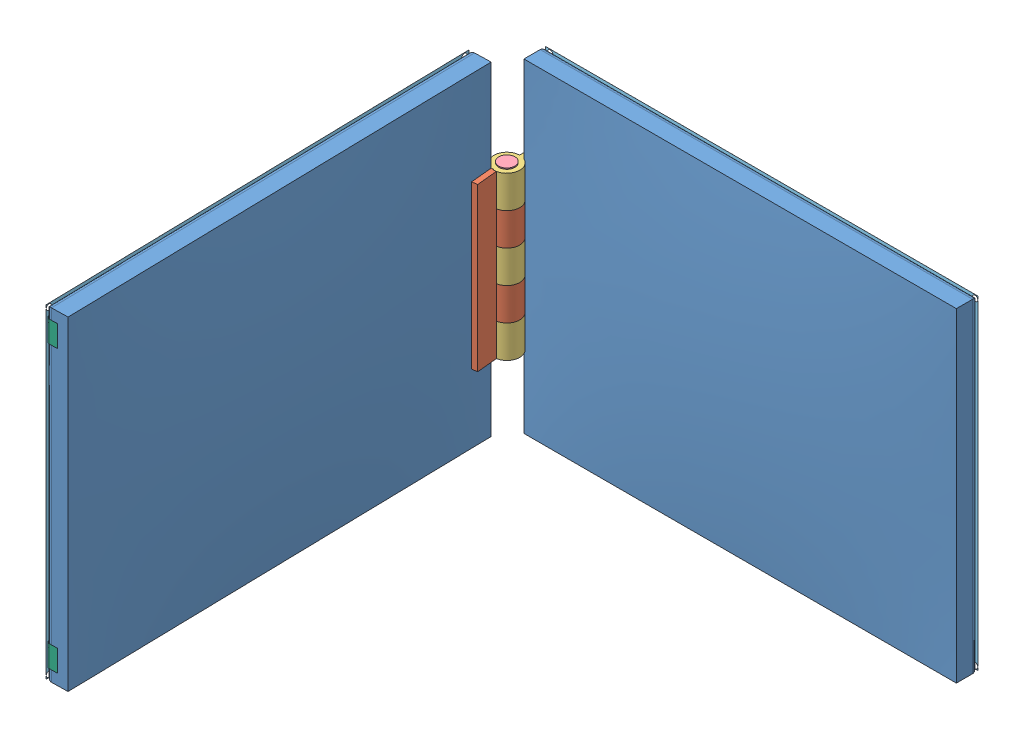
SolidWorks assembly Foldable Seat, configuration Default. Lengths in mm.
Overall size (427.7 305 443.01).
9 component instances, 6 part files, 19 mates.
Components (placement in the parent):
- Seat(1)-1: Seat(1) [Default] at (205.5713 239.5838 256.392) size (400 300 33.33)
- Hinge (2)-2: Hinge (2) [Default] at (-4.9428 213.6304 308.5128) x (0 1 0) z (0.09627 0 0.995355) size (150 24 43.3)
- Hinge (3)-1: Hinge (3) [Default] at (-5.687 213.6304 266.392) x (0 0 -1) z (0 -1 0) size (43.01 24 150)
- Pin Seat-1: Pin Seat [Default] at (-7.9607 288.6304 287.4016) x (-0.117978 0 0.993016) z (0 -1 0) size (15 15 152)
- Bottom-1: Bottom [Default] at (-7.6311 53.8173 266.392) size (400 300 0.01)
- Seat(1)-2: Seat(1) [Default] at (-26.3736 202.6769 508.1818) x (0.021575 0 0.999767) z (0.999767 0 -0.021575) size (400 300 33.33)
- Bottom-2: Bottom [Default] at (-40.9811 58.8173 295.245) x (0.021575 0 0.999767) z (-0.999767 0 0.021575) size (400 300 0.01)
- Stand-2: Stand [Default] at (-22.3282 357.3682 696.1066) x (-0.021575 0 -0.999767) z (0 -1 0) size (20.65 10.65 20)
- Stand-3: Stand [Default] at (-22.3282 97.3682 696.1066) x (-0.021575 0 -0.999767) z (0 -1 0) size (20.65 10.65 20)
Mates (geometry in assembly coordinates):
- Concentric1: concentric anti-aligned: cylinder of Hinge (2)-2 through (-7.9607 168.6304 287.4016) axis (0 1 0) radius 6; cylinder of Hinge (3)-1 through (-7.9607 168.6304 287.4016) axis (0 -1 0) radius 6
- Coincident1: coincident anti-aligned: plane of Hinge (2)-2 through (-7.9607 228.6304 287.4016) normal (0 -1 0); plane of Hinge (3)-1 through (-7.9607 228.6304 287.4016) normal (0 1 0)
- Concentric2: concentric anti-aligned: circle of Hinge (3)-1; cylinder of Pin Seat-1 through (-7.9607 138.6304 287.4016) axis (0 1 0) radius 5.5
- Coincident3: coincident anti-aligned: plane of Hinge (3)-1 through (-3.187 288.6304 256.392) normal (0 1 0); plane of Pin Seat-1 through (-7.9607 288.6304 287.4016) normal (0 -1 0)
- Coincident9: coincident anti-aligned: plane of Seat(1)-1 through (-3.187 368.6304 276.392) normal (-1 0 0); plane of Hinge (3)-1 through (-3.187 213.6304 266.392) normal (1 0 0)
- Coincident13: coincident anti-aligned: plane of Seat(1)-1 through (205.5713 239.5838 256.392) normal (0 0 -1); plane of Bottom-1 through (-7.6311 53.8173 256.392) normal (0 0 1)
- Distance3: distance = 80 mm: line of Hinge (3)-1 through (-3.187 288.6304 256.392) axis (0 0 1); line of Seat(1)-1 through (-3.187 368.6304 276.392) axis (0 0 -1)
- Coincident25: coincident aligned: line of Hinge (3)-1 through (-3.187 138.6304 256.392) axis (0 1 0); line of Bottom-1 through (-3.187 68.6304 256.392) axis (0 1 0)
- Distance5: distance = 80 mm: line of Seat(1)-2 through (-22.3555 368.6304 694.3801) axis (-0.021575 0 -0.999767); line of Hinge (2)-2 through (-3.9801 288.6304 318.4663) axis (-0.09627 0 -0.995355)
- Tangent3: tangent anti-aligned: plane of Hinge (2)-2 through (-9.9195 213.6304 308.9941) normal (-0.995355 0 0.09627); face of Seat(1)-2
- LimitAngle1: limit planar angle = 1.592373 rad aligned: line of Seat(1)-1 through (-3.187 68.6304 276.392) axis (1 0 0); line of Seat(1)-2 through (-2.2523 73.6304 698.9475) axis (-0.021575 0 -0.999767)
- Coincident31: coincident anti-aligned: plane of Seat(1)-2 through (-26.3736 202.6769 508.1818) normal (-0.999767 0 0.021575); plane of Bottom-2 through (-30.9735 58.8173 295.029) normal (0.999767 0 -0.021575)
- Parallel6: parallel anti-aligned: line of Seat(1)-2 through (-10.8822 73.6304 299.0406) axis (0 1 0); line of Bottom-2 through (-30.8776 373.6304 299.4721) axis (0 -1 0)
- Coincident35: coincident: plane of Seat(1)-2 through (-10.8822 73.6304 299.0406) normal (-0.021575 0 -0.999767); line of Bottom-2 through (-30.8776 373.6304 299.4721) axis (0 -1 0)
- Coincident40: coincident aligned: plane of Seat(1)-2 through (-10.8822 373.6304 299.0406) normal (0 1 0); plane of Bottom-2 through (-30.8776 373.6304 299.4721) normal (0 1 0)
- Coincident41: coincident anti-aligned: plane of Bottom-2 through (-30.9835 58.8173 295.0293) normal (-0.999767 0 0.021575); plane of Stand-2 through (-22.3282 357.3682 696.1066) normal (0.999767 0 -0.021575)
- Coincident46: coincident anti-aligned: plane of Seat(1)-2 through (-2.2523 73.6304 698.9475) normal (0.021575 0 0.999767); plane of Stand-2 through (-24.2508 357.3682 699.4222) normal (-0.021575 0 -0.999767)
- Distance7: distance = 10 mm: line of Stand-2 through (-19.2583 363.6304 699.3144) axis (0.999767 0 -0.021575); line of Seat(1)-2 through (-2.2523 373.6304 698.9475) axis (-0.999767 0 0.021575)
- Coincident47: coincident anti-aligned: line of Hinge (2)-2 through (-10.8822 288.6304 299.0406) axis (0 -1 0); line of Seat(1)-2 through (-10.8822 73.6304 299.0406) axis (0 1 0)
